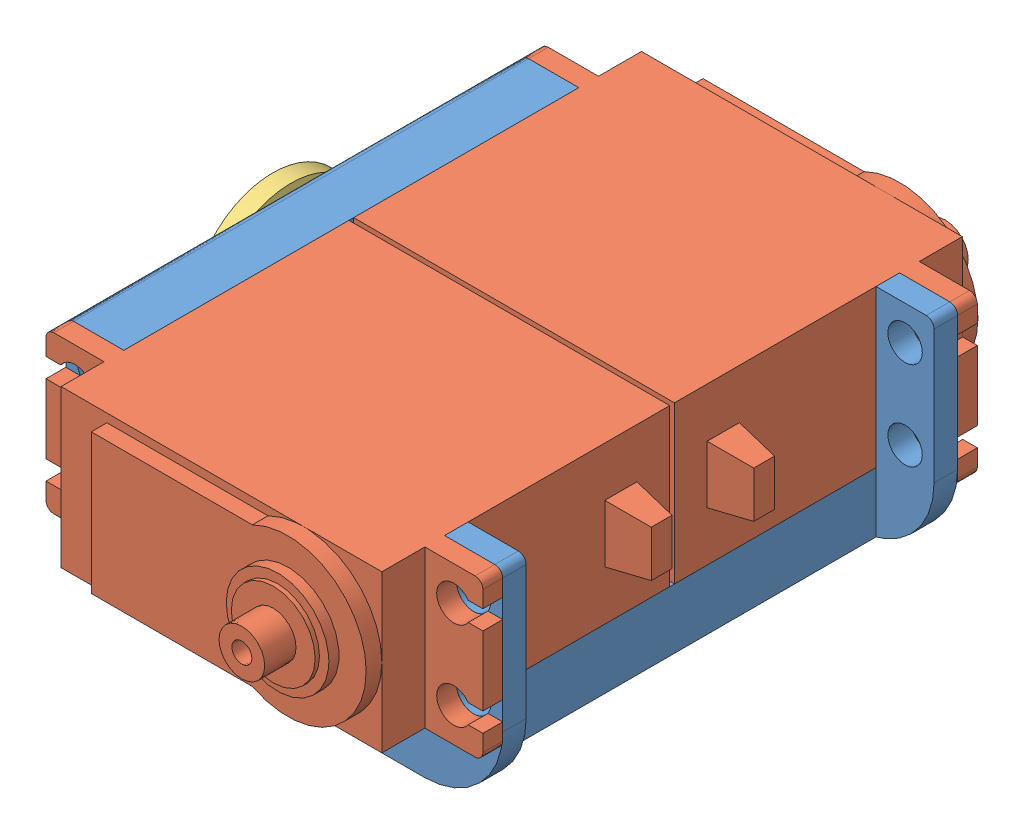
SolidWorks assembly arm2_link2, configuration 기본. Lengths in mm.
Overall size (61 28.4 89.7).
4 component instances, 3 part files, 9 mates.
Components (placement in the parent):
- frame2-1: frame2 [기본] at origin size (55.7 28 58)
- mg946r-2: mg946r [기본] at origin size (55.7 20 44.55)
- mg946r-3: mg946r [기본] at (0 0 -0.6) x (1 0 0) z (0 0 -1) size (55.7 20 44.55)
- HN1_MG946R-3: HN1_MG946R [기본] at (-30.15 0 10.45) x (0 0 -1) z (1 0 0) size (20.8 20.8 5.3)
Mates (geometry in assembly coordinates):
- 일치6: coincident anti-aligned: plane of frame2-1 through (0 0 28.7) normal (0 0 1); plane of mg946r-2 through (27.85 -10 28.7) normal (0 0 -1)
- 일치7: coincident anti-aligned: circle of frame2-1; circle of mg946r-2
- 일치8: coincident anti-aligned: circle of frame2-1; circle of mg946r-2
- 일치9: coincident anti-aligned: plane of frame2-1 through (0 0 -29.3) normal (0 0 -1); plane of mg946r-3 through (27.85 10 -29.3) normal (0 0 1)
- 일치10: coincident aligned: circle of frame2-1; circle of mg946r-3
- 일치11: coincident aligned: circle of frame2-1; circle of mg946r-3
- 동심3: concentric anti-aligned: circle of frame2-1; circle of HN1_MG946R-3
- 일치14: coincident anti-aligned: plane of frame2-1 through (-27.85 10 25.7) normal (-1 0 0); plane of HN1_MG946R-3 through (-27.85 0 0) normal (1 0 0)
- 평행1: parallel anti-aligned: line of frame2-1 through (-27.85 9 28.7) axis (0 0 -1); line of HN1_MG946R-3 through (-27.85 0 -10.4) axis (0 0 1)
